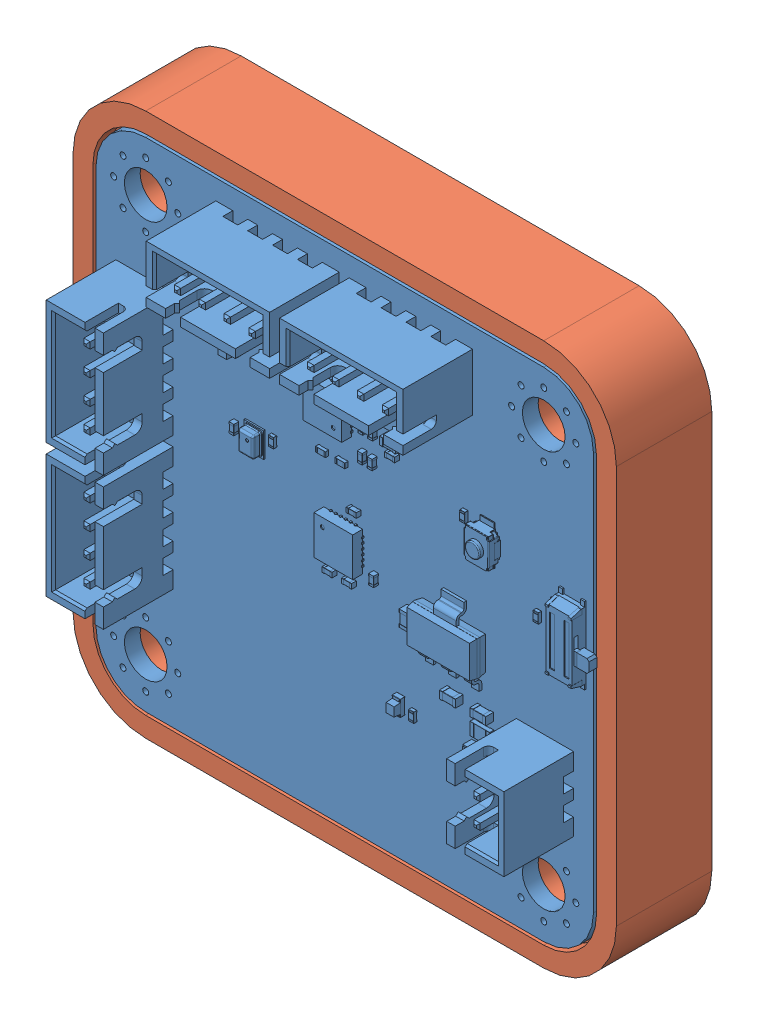
SolidWorks assembly BaroAxel_Brain_VerticalJST_Assembly, configuration Default. Lengths in mm.
Overall size (54.6 54.6 16.64).
2 component instances, 2 part files, 3 mates.
Components (placement in the parent):
- BaroAxel_Brain_VerticalJST_PCB-1: BaroAxel_Brain_VerticalJST_PCB [Default] at (-141.7671 116.4883 50.8) size (50.8 50 10.4)
- BaroAxel_Brain_VerticalJST_Bottom-2: BaroAxel_Brain_VerticalJST_Bottom [Default] at (31.0529 -25.2417 50.8) size (54.6 54.6 16.64)
Mates (geometry in assembly coordinates):
- Bottom_PCB_Front_Coincident: coincident: line of BaroAxel_Brain_VerticalJST_PCB-1 through (-18.9471 -20.2417 50.8) axis (0 1 0); plane of BaroAxel_Brain_VerticalJST_Bottom-2 through (31.0529 -25.2417 50.8) normal (0 0 1)
- Bottom_PCB_Top_Coincident: coincident: line of BaroAxel_Brain_VerticalJST_PCB-1 through (26.0529 -25.2417 50.8) axis (-1 0 0); plane of BaroAxel_Brain_VerticalJST_Bottom-2 through (31.0529 -25.2417 50.8) normal (0 1 0)
- Bottom_PCB_Right_Coincident: coincident: line of BaroAxel_Brain_VerticalJST_PCB-1 through (31.0529 19.7583 50.8) axis (0 -1 0); plane of BaroAxel_Brain_VerticalJST_Bottom-2 through (31.0529 -25.2417 50.8) normal (1 0 0)
